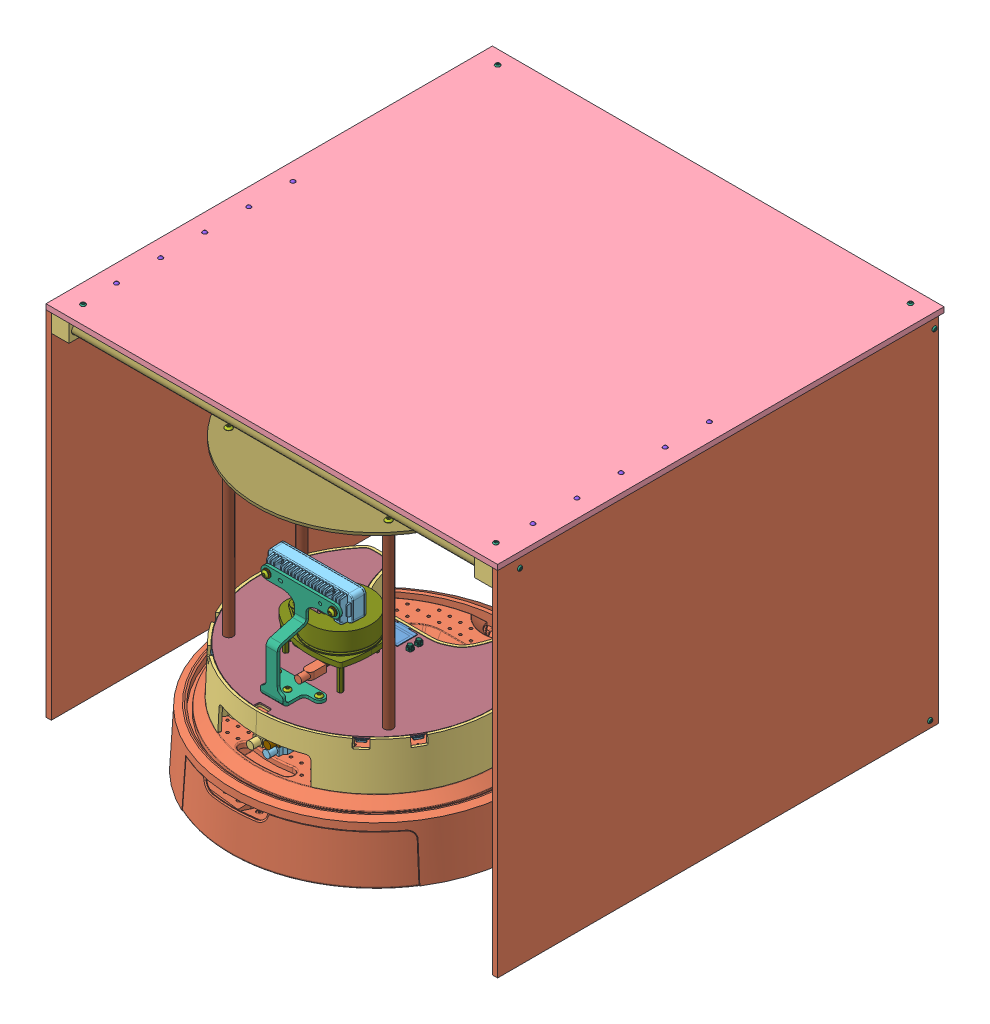
SolidWorks assembly dock_v2_with_robot, configuration Default. Lengths in mm.
Overall size (515 409.05 557.93).
136 component instances, 45 part files, 0 mates.
Components (placement in the parent):
- robot_dock_v2-1: robot_dock_v2 [Default] at (-86.9588 -254.6224 692.6845) x (1 0 0) z (0 -1 0) size (515 507.5 407.6)
  - back_board-1: back_board [Default] at (136.2031 -454.858 73.9405) size (500 6 400)
  - side_board-3: side_board [Default] at (636.2031 51.142 73.9405) x (0 -1 0) z (0 0 1) size (500 6 400)
  - side_board-4: side_board [Default] at (130.2031 51.142 73.9405) x (0 -1 0) z (0 0 1) size (500 6 400)
  - connector-2: connector [Default] at (636.2031 -418.858 75.841) x (-1 0 0) z (0 0 1) size (20 30 23)
  - connector-4: connector [Default] at (636.2031 51.142 75.841) x (-1 0 0) z (0 0 1) size (20 30 23)
  - top_board-1: top_board [Default] at (136.2031 51.142 67.9405) x (1 0 0) z (0 -1 0) size (512 6 506)
  - back_connector-1: back_connector [Default] at (136.2031 -448.858 473.9405) x (1 0 0) z (0 1 0) size (20 30 20)
  - back_connector-2: back_connector [Default] at (616.2031 -448.858 473.9405) x (1 0 0) z (0 1 0) size (20 30 20)
  - Screw_Machine_M3x20-1: Screw_Machine_M3x20 [Default] at (628.2031 -454.858 79.9405) x (-0.837169 0 -0.546944) z (-0.546944 0 0.837169) size (5.5 21.5 5.5)
  - Screw_Machine_M3x20-2: Screw_Machine_M3x20 [Default] at (620.2031 31.142 67.9405) x (-0.900295 -0.43528 0) z (0.43528 -0.900295 0) size (5.5 21.5 5.5)
  - Screw_Machine_M3x20-6: Screw_Machine_M3x20 [Default] at (144.2031 -454.858 79.9405) x (-1 0 0) z (0 0 1) size (5.5 21.5 5.5)
  - Screw_Machine_M3x20-8: Screw_Machine_M3x20 [Default] at (642.2031 -438.858 465.9405) x (0 0.381849 -0.924225) z (0 -0.924225 -0.381849) size (5.5 21.5 5.5)
  - Screw_Machine_M3x20-9: Screw_Machine_M3x20 [Default] at (146.2031 -454.858 451.9405) x (-0.837169 0 -0.546944) z (-0.546944 0 0.837169) size (5.5 21.5 5.5)
  - Screw_Machine_M3x20-10: Screw_Machine_M3x20 [Default] at (130.2031 -443.858 83.9405) x (0 1 0) z (0 0 1) size (5.5 21.5 5.5)
  - Screw_Machine_M3x20-11: Screw_Machine_M3x20 [Default] at (130.2031 -438.858 465.9405) x (0 1 0) z (0 0 1) size (5.5 21.5 5.5)
  - Screw_Machine_M3x20-12: Screw_Machine_M3x20 [Default] at (130.2031 26.142 83.9405) x (0 1 0) z (0 0 1) size (5.5 21.5 5.5)
  - Screw_Machine_M3x20-13: Screw_Machine_M3x20 [Default] at (152.2031 -438.858 67.9405) x (1 0 0) z (0 1 0) size (5.5 21.5 5.5)
  - Screw_Machine_M3x20-14: Screw_Machine_M3x20 [Default] at (620.2031 -438.858 67.9405) x (1 0 0) z (0 1 0) size (5.5 21.5 5.5)
  - Screw_Machine_M3x20-16: Screw_Machine_M3x20 [Default] at (626.2031 -454.858 451.9405) x (-0.837169 0 -0.546944) z (-0.546944 0 0.837169) size (5.5 21.5 5.5)
  - Screw_Machine_M3x20-17: Screw_Machine_M3x20 [Default] at (642.2031 -443.858 83.9405) x (0 0.381849 -0.924225) z (0 -0.924225 -0.381849) size (5.5 21.5 5.5)
  - Screw_Machine_M3x20-19: Screw_Machine_M3x20 [Default] at (152.2031 31.142 67.9405) x (1 0 0) z (0 1 0) size (5.5 21.5 5.5)
  - Screw_Machine_M3x20-20: Screw_Machine_M3x20 [Default] at (642.2031 26.142 83.9405) x (0 0.381849 -0.924225) z (0 -0.924225 -0.381849) size (5.5 21.5 5.5)
  - robot_dock_pilot-1: robot_dock_pilot [Default] at (291.2031 -448.858 473.9405) x (1 0 0) z (0 1 0) size (20 30 20)
  - robot_dock_pilot-2: robot_dock_pilot [Default] at (461.2031 -448.858 473.9405) x (1 0 0) z (0 1 0) size (20 30 20)
  - Led Lamp 5 mm 3-1: Led Lamp 5 mm 3 [Default] at (622.2031 -8.858 74.9405) x (0 0 -1) z (1 0 0) size (35.6 5.45 5.9)
  - Led Lamp 5 mm 3-2: Led Lamp 5 mm 3 [Default] at (150.2031 -208.858 74.9405) x (0 0 -1) z (1 0 0) size (35.6 5.45 5.9)
  - Led Lamp 5 mm 3-3: Led Lamp 5 mm 3 [Default] at (150.2031 -58.858 74.9405) x (0 0 -1) z (1 0 0) size (35.6 5.45 5.9)
  - Led Lamp 5 mm 3-4: Led Lamp 5 mm 3 [Default] at (150.2031 -8.858 74.9405) x (0 0 -1) z (1 0 0) size (35.6 5.45 5.9)
  - Led Lamp 5 mm 3-5: Led Lamp 5 mm 3 [Default] at (622.2031 -208.858 74.9405) x (0 0 -1) z (1 0 0) size (35.6 5.45 5.9)
  - Led Lamp 5 mm 3-6: Led Lamp 5 mm 3 [Default] at (622.2031 -158.858 74.9405) x (0 0 -1) z (1 0 0) size (35.6 5.45 5.9)
  - Led Lamp 5 mm 3-7: Led Lamp 5 mm 3 [Default] at (150.2031 -158.858 74.9405) x (0 0 -1) z (1 0 0) size (35.6 5.45 5.9)
  - Led Lamp 5 mm 3-8: Led Lamp 5 mm 3 [Default] at (150.2031 -108.858 74.9405) x (0 0 -1) z (1 0 0) size (35.6 5.45 5.9)
  - Led Lamp 5 mm 3-10: Led Lamp 5 mm 3 [Default] at (622.2031 -108.858 74.9405) x (0 0 -1) z (1 0 0) size (35.6 5.45 5.9)
  - Led Lamp 5 mm 3-11: Led Lamp 5 mm 3 [Default] at (622.2031 -58.858 74.9405) x (0 0 -1) z (0.182556 -0.983195 0) size (35.6 5.45 5.9)
  - connector-10: connector [Default] at (136.2031 51.142 92.04) x (1 0 0) z (0 0 -1) size (20 30 23)
  - connector-11: connector [Default] at (136.2031 -418.858 92.04) x (1 0 0) z (0 0 -1) size (20 30 23)
  - Dock-1: Dock [Default] at (311.2031 -448.858 473.9405) x (0 1 0) z (-1 0 0) size (200.3 135.31 152.91)
  - Screw_Machine_M3x20-21: Screw_Machine_M3x20 [Default] at (471.2031 -454.858 451.9405) x (0.825172 0 -0.564882) z (-0.564882 0 -0.825172) size (5.5 21.5 5.5)
  - Screw_Machine_M3x20-22: Screw_Machine_M3x20 [Default] at (301.2031 -454.858 451.9405) x (0.825172 0 -0.564882) z (-0.564882 0 -0.825172) size (5.5 21.5 5.5)
  - Screw_Machine_M3x20-23: Screw_Machine_M3x20 [Default] at (301.2031 -454.858 465.9405) x (0.825172 0 -0.564882) z (-0.564882 0 -0.825172) size (5.5 21.5 5.5)
  - Screw_Machine_M3x20-24: Screw_Machine_M3x20 [Default] at (471.2031 -454.858 465.9405) x (0.825172 0 -0.564882) z (-0.564882 0 -0.825172) size (5.5 21.5 5.5)
  - esp_module-1: esp_module [Default] at (410.8988 -405.3381 199.9456) x (-1 0 0) z (0 0 1) size (31.5 18.14 59.98)
    - Lolin NodeMCU ESP8266 V3-1: Lolin NodeMCU ESP8266 V3 [Default] at (25.4457 33.9199 72.0949) size (31.5 13.14 59.98)
    - esp_backplate-1: esp_backplate [Default] at (2.8678 40.5199 10.4032) size (31.5 8 58.1)
  - stick-1: stick [Default] at (139.2031 43.142 83.9405) x (0 -1 0) z (0 0 1) size (9 494 9)
- turtlebot4_official.STEP-1: turtlebot4_official.STEP [Default] at (302.4645 -728.5173 629.2859) x (0 0 -1) z (0 1 0) size (342.22 344 352.66)
  - 025619_PCBA, Shell-shape-O273 X 230.STEP-1: 025619_PCBA, Shell-shape-O273 X 230.STEP [Default] at (-0.0061 -0.0131 144.3855) x (1 -0.00006 0) z (0 0 1) size (219.76 262.89 19.84)
    - 025618_PCB, Shell-shape-O273 X 230.STEP-1: 025618_PCB, Shell-shape-O273 X 230.STEP [Default] at origin size (219.76 262.89 1.59)
    - keystone-PN953.STEP-1: keystone-PN953.STEP [Default] at (-94.6422 79.4142 -0.18) x (0.642788 0.766044 0) z (-0.766044 0.642788 0) size (11.93 3.62 9.75)
    - keystone-PN953.STEP-2: keystone-PN953.STEP [Default] at (-61.7733 106.9945 -0.18) x (0.866025 0.5 0) z (-0.5 0.866025 0) size (11.93 3.62 9.75)
    - keystone-PN953.STEP-3: keystone-PN953.STEP [Default] at (-94.6422 -79.4142 -0.18) x (-0.642788 0.766044 0) z (-0.766044 -0.642788 0) size (11.93 3.62 9.75)
    - keystone-PN953.STEP-4: keystone-PN953.STEP [Default] at (-61.7733 -106.9945 -0.18) x (-0.866025 0.5 0) z (-0.5 -0.866025 0) size (11.93 3.62 9.75)
    - keystone-PN953.STEP-5: keystone-PN953.STEP [Default] at (-25.9953 -35.52 -0.36) x (1 0 0) z (0 0 -1) size (11.93 3.62 9.75)
    - keystone-PN953.STEP-6: keystone-PN953.STEP [Default] at (-25.9953 22.49 -0.36) x (-1 0 0) z (0 0 -1) size (11.93 3.62 9.75)
    - EVPAS-CD-B1A+ABDEF-C1A.STEP-1: EVPAS-CD-B1A+ABDEF-C1A.STEP [Default] at (12.4588 -26.546 1.57) x (1 0 0) z (0 -1 0) size (6.1 5.01 7)
    - EVPAS-CD-B1A+ABDEF-C1A.STEP-2: EVPAS-CD-B1A+ABDEF-C1A.STEP [Default] at (22.4058 -26.546 1.57) x (1 0 0) z (0 -1 0) size (6.1 5.01 7)
    - EVPAS-CD-B1A+ABDEF-C1A.STEP-3: EVPAS-CD-B1A+ABDEF-C1A.STEP [Default] at (12.4588 26.5161 1.57) x (1 0 0) z (0 -1 0) size (6.1 5.01 7)
    - EVPAS-CD-B1A+ABDEF-C1A.STEP-4: EVPAS-CD-B1A+ABDEF-C1A.STEP [Default] at (22.4058 26.5161 1.57) x (1 0 0) z (0 -1 0) size (6.1 5.01 7)
    - LED - IN-P32DATRG_Item Name from PLM.STEP-1: LED - IN-P32DATRG_Item Name from PLM.STEP [Default] at (4.5001 -11.0459 1.57) size (2.8 3.5 1.9)
    - LED - IN-P32DATRG_Item Name from PLM.STEP-2: LED - IN-P32DATRG_Item Name from PLM.STEP [Default] at (4.5001 11.016 1.57) size (2.8 3.5 1.9)
    - LED - IN-P32DATRG_Item Name from PLM.STEP-3: LED - IN-P32DATRG_Item Name from PLM.STEP [Default] at (-8.6946 -20.1308 1.57) size (2.8 3.5 1.9)
    - LED - IN-P32DATRG_Item Name from PLM.STEP-4: LED - IN-P32DATRG_Item Name from PLM.STEP [Default] at (-8.6946 -10.0579 1.57) size (2.8 3.5 1.9)
    - LED - IN-P32DATRG_Item Name from PLM.STEP-5: LED - IN-P32DATRG_Item Name from PLM.STEP [Default] at (-8.6946 0.0149 1.57) size (2.8 3.5 1.9)
    - LED - IN-P32DATRG_Item Name from PLM.STEP-6: LED - IN-P32DATRG_Item Name from PLM.STEP [Default] at (-8.6946 10.0878 1.57) size (2.8 3.5 1.9)
    - LED - IN-P32DATRG_Item Name from PLM.STEP-7: LED - IN-P32DATRG_Item Name from PLM.STEP [Default] at (-8.6946 20.1606 1.57) size (2.8 3.5 1.9)
    - keystone-PN953.STEP-7: keystone-PN953.STEP [Default] at (-15.9953 81.47 -0.36) x (1 0 0) z (0 0 -1) size (11.93 3.62 9.75)
    - GPIO-PCB Header_40pin.STEP-1: GPIO-PCB Header_40pin.STEP [Default] at (-74.59 -14.413 0) x (1 0 0) z (0 1 0) size (50.81 13.47 4.84)
    - GPIO-PCB Header_16pin.STEP-1: GPIO-PCB Header_16pin.STEP [Default] at (-74.59 14.413 0) x (1 0 0) z (0 1 0) size (20.33 13.47 4.84)
    - 025904_As Installed.STEP-1: 025904_As Installed.STEP [Default] at (18.7547 -0.0149 2.997) size (34.72 34.5 3.33)
  - 026292-OS_1__Item Name from PLM.STEP-1: 026292-OS_1__Item Name from PLM.STEP [Default] at (0 0 37.8855) x (0 1 0) z (1 0 0) size (344 96.08 342.22)
  - 025441_4_Riser Bracket-O275, Plastic, Black.STEP-1: 025441_4_Riser Bracket-O275, Plastic, Black.STEP [Default] at (0.0007 -0.0149 93.3855) size (229.59 273.19 53.38)
  - 025614_1_Screw, Cap, Flat Head-M3.5 X 10, Steal, Zinc Plate.STEP-1: 025614_1_Screw, Cap, Flat Head-M3.5 X 10, Steal, Zinc Plate.STEP [Default] at (72 96 92.546) x (0.995283 0.09701 0) z (0 0 1) size (7.3 7.3 10.01)
  - 025614_1_Screw, Cap, Flat Head-M3.5 X 10, Steal, Zinc Plate.STEP-2: 025614_1_Screw, Cap, Flat Head-M3.5 X 10, Steal, Zinc Plate.STEP [Default] at (12 36 92.546) x (0.967312 0.253588 0) z (0 0 1) size (7.3 7.3 10.01)
  - 025614_1_Screw, Cap, Flat Head-M3.5 X 10, Steal, Zinc Plate.STEP-3: 025614_1_Screw, Cap, Flat Head-M3.5 X 10, Steal, Zinc Plate.STEP [Default] at (12 -36 92.546) x (0.544294 -0.838895 0) z (0 0 1) size (7.3 7.3 10.01)
  - 025614_1_Screw, Cap, Flat Head-M3.5 X 10, Steal, Zinc Plate.STEP-4: 025614_1_Screw, Cap, Flat Head-M3.5 X 10, Steal, Zinc Plate.STEP [Default] at (72 -96 92.546) x (0.325351 0.945593 0) z (0 0 1) size (7.3 7.3 10.01)
  - 025614_1_Screw, Cap, Flat Head-M3.5 X 10, Steal, Zinc Plate.STEP-5: 025614_1_Screw, Cap, Flat Head-M3.5 X 10, Steal, Zinc Plate.STEP [Default] at (-36 -108 92.546) x (0.804099 0.594496 0) z (0 0 1) size (7.3 7.3 10.01)
  - 025614_1_Screw, Cap, Flat Head-M3.5 X 10, Steal, Zinc Plate.STEP-6: 025614_1_Screw, Cap, Flat Head-M3.5 X 10, Steal, Zinc Plate.STEP [Default] at (-96 -60 92.546) x (0.770543 0.637388 0) z (0 0 1) size (7.3 7.3 10.01)
  - 025614_1_Screw, Cap, Flat Head-M3.5 X 10, Steal, Zinc Plate.STEP-7: 025614_1_Screw, Cap, Flat Head-M3.5 X 10, Steal, Zinc Plate.STEP [Default] at (-96 60 92.546) x (0.764306 0.644854 0) z (0 0 1) size (7.3 7.3 10.01)
  - 025961_1_Camera, RGBD, Luxonis OAK-D-Pro.STEP-1: 025961_1_Camera, RGBD, Luxonis OAK-D-Pro.STEP [Default] at (-69.2695 -44.509 249.7055) x (0.00006 1 0) z (1 -0.00006 0) size (97.03 29.53 22.93)
  - 025426_6_Bracket, Camera, Aluminium Alloy.STEP-1: 025426_6_Bracket, Camera, Aluminium Alloy.STEP [Default] at (-118.0061 -0.0061 145.9555) x (1 -0.00006 0) z (0 0 1) size (36 89 99)
  - 025609_1_Screw, Cap, Round Head-M4x0.7 X 10, Stainless Steel Type 18-8, Black Oxide.STEP-1: 025609_1_Screw, Cap, Round Head-M4x0.7 X 10, Stainless Steel Type 18-8, Black Oxide.STEP [Default] at (-88.0075 -24.0078 145.3155) x (0.93747 0.348067 0) z (0 0 1) size (7.6 7.6 12.21)
  - 025609_1_Screw, Cap, Round Head-M4x0.7 X 10, Stainless Steel Type 18-8, Black Oxide.STEP-2: 025609_1_Screw, Cap, Round Head-M4x0.7 X 10, Stainless Steel Type 18-8, Black Oxide.STEP [Default] at (-100.0061 -0.0071 145.3155) x (0.79095 0.61188 0) z (0 0 1) size (7.6 7.6 12.21)
  - 025609_1_Screw, Cap, Round Head-M4x0.7 X 10, Stainless Steel Type 18-8, Black Oxide.STEP-3: 025609_1_Screw, Cap, Round Head-M4x0.7 X 10, Stainless Steel Type 18-8, Black Oxide.STEP [Default] at (-88.0046 23.9922 145.3155) x (0.731026 0.682349 0) z (0 0 1) size (7.6 7.6 12.21)
  - 010898_Nut, Hex-M4 x 0.7 X 3.2, Type 18-8 Stainless Steel.STEP-1: 010898_Nut, Hex-M4 x 0.7 X 3.2, Type 18-8 Stainless Steel.STEP [Default] at (-100.0061 -0.0071 141.8855) x (0.923728 0.383049 0) z (0 0 -1) size (8.09 8.1 3.22)
  - 025610_1_Washer, Flat-O4.3 X O9 X 0.9, Stainless Steel, Black Oxide.STEP-1: 025610_1_Washer, Flat-O4.3 X O9 X 0.9, Stainless Steel, Black Oxide.STEP [Default] at (-100.0061 -0.0071 144.3855) x (-0.923728 -0.383049 0) z (0 0 -1) size (9 9 0.9)
  - 010898_Nut, Hex-M4 x 0.7 X 3.2, Type 18-8 Stainless Steel.STEP-2: 010898_Nut, Hex-M4 x 0.7 X 3.2, Type 18-8 Stainless Steel.STEP [Default] at (-88.0075 -24.0078 141.8855) x (0.85131 0.524663 0) z (0 0 -1) size (8.09 8.1 3.22)
  - 025610_1_Washer, Flat-O4.3 X O9 X 0.9, Stainless Steel, Black Oxide.STEP-2: 025610_1_Washer, Flat-O4.3 X O9 X 0.9, Stainless Steel, Black Oxide.STEP [Default] at (-88.0075 -24.0078 144.3855) x (-0.85131 -0.524663 0) z (0 0 -1) size (9 9 0.9)
  - 010898_Nut, Hex-M4 x 0.7 X 3.2, Type 18-8 Stainless Steel.STEP-3: 010898_Nut, Hex-M4 x 0.7 X 3.2, Type 18-8 Stainless Steel.STEP [Default] at (-88.0046 23.9922 141.8855) x (0.777574 0.628792 0) z (0 0 -1) size (8.09 8.1 3.22)
  - 025610_1_Washer, Flat-O4.3 X O9 X 0.9, Stainless Steel, Black Oxide.STEP-3: 025610_1_Washer, Flat-O4.3 X O9 X 0.9, Stainless Steel, Black Oxide.STEP [Default] at (-88.0046 23.9922 144.3855) x (-0.777574 -0.628792 0) z (0 0 -1) size (9 9 0.9)
  - 025609_1_Screw, Cap, Round Head-M4x0.7 X 10, Stainless Steel Type 18-8, Black Oxide.STEP-4: 025609_1_Screw, Cap, Round Head-M4x0.7 X 10, Stainless Steel Type 18-8, Black Oxide.STEP [Default] at (-83.6246 37.4919 237.9555) x (0.000005 0.080023 0.996793) z (-1 0.00006 0) size (7.6 7.6 12.21)
  - 025609_1_Screw, Cap, Round Head-M4x0.7 X 10, Stainless Steel Type 18-8, Black Oxide.STEP-5: 025609_1_Screw, Cap, Round Head-M4x0.7 X 10, Stainless Steel Type 18-8, Black Oxide.STEP [Default] at (-83.6291 -37.5081 237.9555) x (0.000033 0.560382 -0.828234) z (-1 0.00006 0) size (7.6 7.6 12.21)
  - 025610_1_Washer, Flat-O4.3 X O9 X 0.9, Stainless Steel, Black Oxide.STEP-4: 025610_1_Washer, Flat-O4.3 X O9 X 0.9, Stainless Steel, Black Oxide.STEP [Default] at (-86.4246 37.4921 237.9555) x (-0.000007 -0.116927 -0.993141) z (1 -0.00006 0) size (9 9 0.9)
  - 025610_1_Washer, Flat-O4.3 X O9 X 0.9, Stainless Steel, Black Oxide.STEP-5: 025610_1_Washer, Flat-O4.3 X O9 X 0.9, Stainless Steel, Black Oxide.STEP [Default] at (-86.4291 -37.5079 237.9555) x (-0.000002 -0.035095 -0.999384) z (1 -0.00006 0) size (9 9 0.9)
  - 026387_1_Washer, Locking, Split-DIN 7980 M4 X 1.1, Steel, Black.STEP-1: 026387_1_Washer, Locking, Split-DIN 7980 M4 X 1.1, Steel, Black.STEP [Default] at (-87.5246 37.4921 237.9555) x (0 0.00006 -1) z (1 -0.00006 0) size (7 7 2.31)
  - 026387_1_Washer, Locking, Split-DIN 7980 M4 X 1.1, Steel, Black.STEP-2: 026387_1_Washer, Locking, Split-DIN 7980 M4 X 1.1, Steel, Black.STEP [Default] at (-87.5291 -37.5079 237.9555) x (0 0.00006 -1) z (1 -0.00006 0) size (7 7 2.31)
  - 025481_4_Standoff, Threaded, Round-Male-Female, M4 X 200, Aluminum.STEP-1: 025481_4_Standoff, Threaded, Round-Male-Female, M4 X 200, Aluminum.STEP [Default] at (30.6302 114.2957 241.9555) x (0 0 -1) z (-0.212288 0.977207 0) size (208 10 10)
  - 025481_4_Standoff, Threaded, Round-Male-Female, M4 X 200, Aluminum.STEP-2: 025481_4_Standoff, Threaded, Round-Male-Female, M4 X 200, Aluminum.STEP [Default] at (-76.0687 90.6411 241.9555) x (0 0 -1) z (-0.247385 -0.968917 0) size (208 10 10)
  - 025481_4_Standoff, Threaded, Round-Male-Female, M4 X 200, Aluminum.STEP-3: 025481_4_Standoff, Threaded, Round-Male-Female, M4 X 200, Aluminum.STEP [Default] at (30.6302 -114.2957 241.9555) x (0 0 -1) z (0.68149 -0.731827 0) size (208 10 10)
  - 025481_4_Standoff, Threaded, Round-Male-Female, M4 X 200, Aluminum.STEP-4: 025481_4_Standoff, Threaded, Round-Male-Female, M4 X 200, Aluminum.STEP [Default] at (-76.0687 -90.6411 241.9555) x (0 0 -1) z (0.57449 0.818512 0) size (208 10 10)
  - 025394_Plate, Sensor Integration.STEP-1: 025394_Plate, Sensor Integration.STEP [Default] at (0.0007 -0.0149 345.9555) size (250 270 3)
  - 025609_1_Screw, Cap, Round Head-M4x0.7 X 10, Stainless Steel Type 18-8, Black Oxide.STEP-6: 025609_1_Screw, Cap, Round Head-M4x0.7 X 10, Stainless Steel Type 18-8, Black Oxide.STEP [Default] at (30.6302 114.2957 345.0555) size (7.6 7.6 12.21)
  - 025609_1_Screw, Cap, Round Head-M4x0.7 X 10, Stainless Steel Type 18-8, Black Oxide.STEP-7: 025609_1_Screw, Cap, Round Head-M4x0.7 X 10, Stainless Steel Type 18-8, Black Oxide.STEP [Default] at (30.6302 -114.2957 345.0555) x (0.987351 0.158553 0) z (0 0 1) size (7.6 7.6 12.21)
  - 025609_1_Screw, Cap, Round Head-M4x0.7 X 10, Stainless Steel Type 18-8, Black Oxide.STEP-8: 025609_1_Screw, Cap, Round Head-M4x0.7 X 10, Stainless Steel Type 18-8, Black Oxide.STEP [Default] at (-76.0687 -90.6411 345.0555) x (0.959125 0.282984 0) z (0 0 1) size (7.6 7.6 12.21)
  - 025609_1_Screw, Cap, Round Head-M4x0.7 X 10, Stainless Steel Type 18-8, Black Oxide.STEP-9: 025609_1_Screw, Cap, Round Head-M4x0.7 X 10, Stainless Steel Type 18-8, Black Oxide.STEP [Default] at (-76.0687 90.6411 345.0555) x (0.928571 0.371154 0) z (0 0 1) size (7.6 7.6 12.21)
  - 024051_1_Computer, Single Board, SBC-Raspberry Pi 4, 2 GB.STEP-1: 024051_1_Computer, Single Board, SBC-Raspberry Pi 4, 2 GB.STEP [Default] at (-46.6082 -7.1031 99.1855) x (-1 0 0) z (0 1 0) size (89 19.93 58.4)
  - 025552_2_Standoff, Threaded, Hex - Male-Female, M2.5 X 5, Hex Size 4.5 mm, Aluminum.STEP-1: 025552_2_Standoff, Threaded, Hex - Male-Female, M2.5 X 5, Hex Size 4.5 mm, Aluminum.STEP [Default] at (-7.6082 17.3969 93.9355) x (0 0 -1) z (-0.895183 -0.445699 0) size (8.9 5.21 4.51)
  - 025552_2_Standoff, Threaded, Hex - Male-Female, M2.5 X 5, Hex Size 4.5 mm, Aluminum.STEP-2: 025552_2_Standoff, Threaded, Hex - Male-Female, M2.5 X 5, Hex Size 4.5 mm, Aluminum.STEP [Default] at (-65.6082 -31.6031 93.9455) x (0 0 -1) z (-0.813193 -0.581995 0) size (8.9 5.21 4.51)
  - 025552_2_Standoff, Threaded, Hex - Male-Female, M2.5 X 5, Hex Size 4.5 mm, Aluminum.STEP-3: 025552_2_Standoff, Threaded, Hex - Male-Female, M2.5 X 5, Hex Size 4.5 mm, Aluminum.STEP [Default] at (-7.6082 -31.6031 93.9355) x (0 0 -1) z (-0.813193 -0.581995 0) size (8.9 5.21 4.51)
  - 025552_2_Standoff, Threaded, Hex - Male-Female, M2.5 X 5, Hex Size 4.5 mm, Aluminum.STEP-4: 025552_2_Standoff, Threaded, Hex - Male-Female, M2.5 X 5, Hex Size 4.5 mm, Aluminum.STEP [Default] at (-65.6082 17.3969 93.9355) x (0 0 -1) z (-0.813193 -0.581995 0) size (8.9 5.21 4.51)
  - 025616_1_Screw, Cap, Round Head-M2.5x0.45 X 4, Stainless Steel Type 18-8, Black Oxide.STEP-1: 025616_1_Screw, Cap, Round Head-M2.5x0.45 X 4, Stainless Steel Type 18-8, Black Oxide.STEP [Default] at (-65.6082 17.3969 101.4755) x (-0.922007 -0.387173 0) z (0 0 1) size (4.5 4.5 5.5)
  - 025616_1_Screw, Cap, Round Head-M2.5x0.45 X 4, Stainless Steel Type 18-8, Black Oxide.STEP-2: 025616_1_Screw, Cap, Round Head-M2.5x0.45 X 4, Stainless Steel Type 18-8, Black Oxide.STEP [Default] at (-65.6082 -31.6031 101.4755) x (-0.848957 -0.528462 0) z (0 0 1) size (4.5 4.5 5.5)
  - 025616_1_Screw, Cap, Round Head-M2.5x0.45 X 4, Stainless Steel Type 18-8, Black Oxide.STEP-3: 025616_1_Screw, Cap, Round Head-M2.5x0.45 X 4, Stainless Steel Type 18-8, Black Oxide.STEP [Default] at (-7.6082 17.3969 101.4755) x (-0.774756 -0.63226 0) z (0 0 1) size (4.5 4.5 5.5)
  - 025616_1_Screw, Cap, Round Head-M2.5x0.45 X 4, Stainless Steel Type 18-8, Black Oxide.STEP-4: 025616_1_Screw, Cap, Round Head-M2.5x0.45 X 4, Stainless Steel Type 18-8, Black Oxide.STEP [Default] at (-7.6082 -31.6031 101.4755) x (-0.712449 -0.701724 0) z (0 0 1) size (4.5 4.5 5.5)
  - 025962_1_LIDAR, RPLidar A1M8, Slamtec.STEP-1: 025962_1_LIDAR, RPLidar A1M8, Slamtec.STEP [Default] at (-76.5474 -37.1117 145.9555) x (0.00006 1 0) z (1 -0.00006 0) size (97.35 55.07 71.45)
  - 026634_1_Screw, Cap, Socket Head-M2.5x0.45 X 6, Stainless Steel Type 316.STEP-1: 026634_1_Screw, Cap, Socket Head-M2.5x0.45 X 6, Stainless Steel Type 316.STEP [Default] at (-12.0078 -28.0124 142.8855) x (-0.959321 -0.282317 0) z (0 0 -1) size (4.7 4.7 7.5)
  - 026634_1_Screw, Cap, Socket Head-M2.5x0.45 X 6, Stainless Steel Type 316.STEP-2: 026634_1_Screw, Cap, Socket Head-M2.5x0.45 X 6, Stainless Steel Type 316.STEP [Default] at (-20.0036 41.9881 142.8855) x (-0.902424 -0.430849 0) z (0 0 -1) size (4.7 4.7 7.5)
  - 026634_1_Screw, Cap, Socket Head-M2.5x0.45 X 6, Stainless Steel Type 316.STEP-3: 026634_1_Screw, Cap, Socket Head-M2.5x0.45 X 6, Stainless Steel Type 316.STEP [Default] at (-60.0036 41.9905 142.8855) x (-0.840218 -0.542249 0) z (0 0 -1) size (4.7 4.7 7.5)
  - 026634_1_Screw, Cap, Socket Head-M2.5x0.45 X 6, Stainless Steel Type 316.STEP-4: 026634_1_Screw, Cap, Socket Head-M2.5x0.45 X 6, Stainless Steel Type 316.STEP [Default] at (-68.0078 -28.009 142.8855) x (-0.786015 -0.618207 0) z (0 0 -1) size (4.7 4.7 7.5)
  - Create3 Weight Pack_Item Name from PLM.STEP-1: Create3 Weight Pack_Item Name from PLM.STEP [Default] at (193.0236 145.8095 86.626) x (0.225602 -0.97422 0) z (0.959419 0.222174 -0.173648) size (48.09 14.03 30.89)
  - Create3 Weight Pack_Item Name from PLM.STEP-2: Create3 Weight Pack_Item Name from PLM.STEP [Default] at (193.0236 145.8095 95.626) x (0.225602 -0.97422 0) z (0.959419 0.222174 -0.173648) size (48.09 14.03 30.89)
  - Create3 Weight Pack_Item Name from PLM.STEP-3: Create3 Weight Pack_Item Name from PLM.STEP [Default] at (194.4529 -142.3863 109.1449) x (0.200558 0.979682 0) z (0.964798 -0.197511 0.173648) size (48.09 14.03 30.89)
  - Create3 Weight Pack_Item Name from PLM.STEP-4: Create3 Weight Pack_Item Name from PLM.STEP [Default] at (194.4529 -142.3863 118.1449) x (0.200558 0.979682 0) z (0.964798 -0.197511 0.173648) size (48.09 14.03 30.89)
  - 025740_1_Nut, Hex-M2.5 x 0.45 X 2.1, Steel Class 8, Zinc Plate.STEP-1: 025740_1_Nut, Hex-M2.5 x 0.45 X 2.1, Steel Class 8, Zinc Plate.STEP [Default] at (-65.6082 17.3969 89.6355) size (5.78 5.78 2.01)
  - 025740_1_Nut, Hex-M2.5 x 0.45 X 2.1, Steel Class 8, Zinc Plate.STEP-2: 025740_1_Nut, Hex-M2.5 x 0.45 X 2.1, Steel Class 8, Zinc Plate.STEP [Default] at (-65.6082 -31.6031 89.6355) size (5.78 5.78 2.01)
  - 025740_1_Nut, Hex-M2.5 x 0.45 X 2.1, Steel Class 8, Zinc Plate.STEP-3: 025740_1_Nut, Hex-M2.5 x 0.45 X 2.1, Steel Class 8, Zinc Plate.STEP [Default] at (-7.6082 -31.6031 89.6355) size (5.78 5.78 2.01)
  - 025740_1_Nut, Hex-M2.5 x 0.45 X 2.1, Steel Class 8, Zinc Plate.STEP-4: 025740_1_Nut, Hex-M2.5 x 0.45 X 2.1, Steel Class 8, Zinc Plate.STEP [Default] at (-7.6082 17.3969 89.6355) x (-0.997343 0.072845 0) z (0 0 1) size (5.78 5.78 2.01)
  - 025614_1_Screw, Cap, Flat Head-M3.5 X 10, Steal, Zinc Plate.STEP-8: 025614_1_Screw, Cap, Flat Head-M3.5 X 10, Steal, Zinc Plate.STEP [Default] at (-36 108 92.546) x (0.652394 0.75788 0) z (0 0 1) size (7.3 7.3 10.01)
  - 025944_2_Micro B ONLY.STEP-1: 025944_2_Micro B ONLY.STEP [Default] at (-205.6815 -7.5008 160.7555) x (0.00006 1 0) z (0 0 1) size (10 32.6 8.01)
  - 025944_2_USB A ONLY.STEP-1: 025944_2_USB A ONLY.STEP [Default] at (-240.7332 11.8969 103.9655) x (0 1 0) z (0 0 -1) size (16.5 47.05 8.45)
  - 025941_2_90 Deg ONLY.STEP-1: 025941_2_90 Deg ONLY.STEP [Default] at (-66.0541 -121.4542 215.4267) x (0 0 1) z (1 -0.00006 0) size (21.1 29 7)
  - 025941_2_USB A ONLY.STEP-1: 025941_2_USB A ONLY.STEP [Default] at (-242.0532 -6.1031 104.1255) x (0 -1 0) z (0 0 1) size (16.5 47.05 8.45)
  - 025942_1_90 Deg ONLY.STEP-1: 025942_1_90 Deg ONLY.STEP [Default] at (-155.8082 32.7969 101.5655) x (0 -1 0) z (0 0 -1) size (21.1 29 7)
  - 025942_1_USB C ONLY.STEP-1: 025942_1_USB C ONLY.STEP [Default] at (-220.2485 -60.2044 70.0453) x (0.000224 1 0) z (0 0 -1) size (13 36 7)
  - 025943_1_USB B ONLY.STEP-1: 025943_1_USB B ONLY.STEP [Default] at (-65.4395 138.7324 138.0655) x (1 -0.000138 0) z (0 0 1) size (28 26.85 13.5)
  - 025943_1_USB A ONLY.STEP-1: 025943_1_USB A ONLY.STEP [Default] at (-206.1782 -6.1031 112.6255) x (0 -1 0) z (0 0 1) size (16.5 47.05 8.45)
